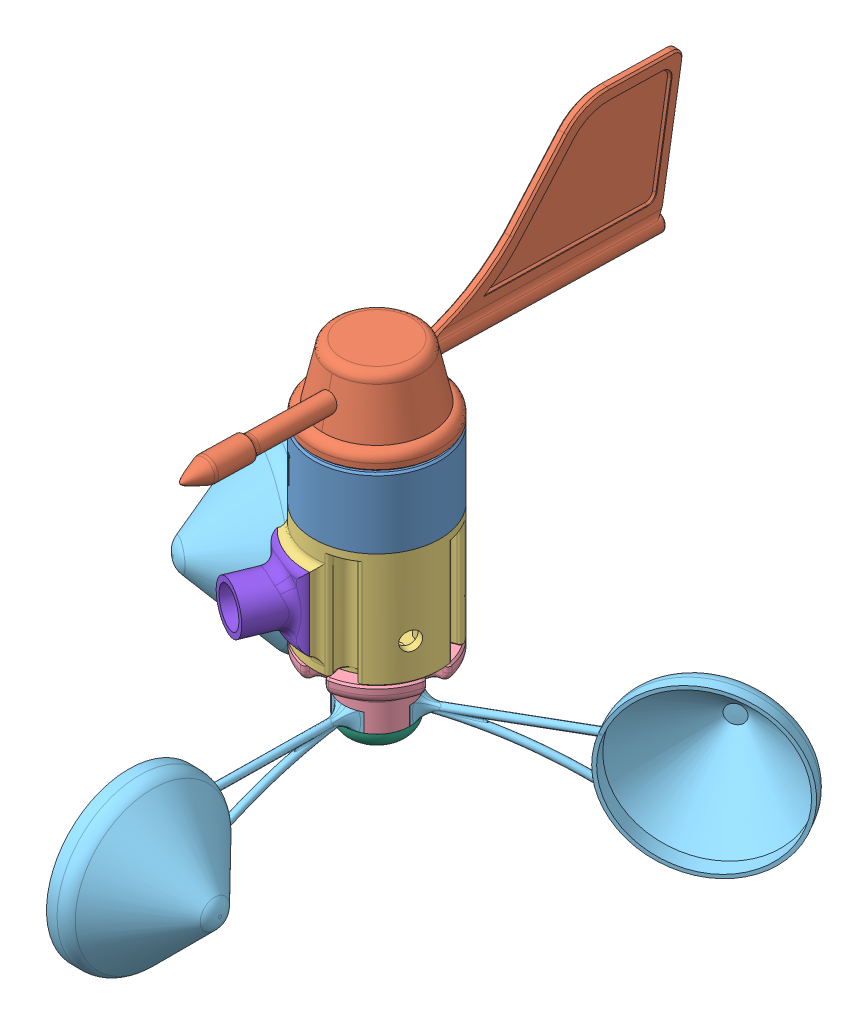
SolidWorks assembly Сборка1, configuration По умолчанию. Lengths in mm.
Overall size (335.22 291.91 357.86).
11 component instances, 8 part files, 27 mates.
Components (placement in the parent):
- втулка1-1: втулка1 [По умолчанию] at (37.1698 47.1282 35.2147) size (69 44 69)
- Деталь2-1: Деталь2 [По умолчанию] at (37.1698 48 35.2147) x (0.999741 0 0.022754) z (-0.022754 0 0.999741) size (69 101.04 267.99)
- втулка2-3: втулка2 [По умолчанию] at (37.1698 -53.8718 35.2147) x (-0.92388 0 0.382683) z (0.382683 0 0.92388) size (71.14 69 71.14)
- Деталь3-2: Деталь3 [По умолчанию] at (37.1698 -53.8718 35.2147) x (-0.999917 0 -0.012913) z (-0.012913 0 0.999917) size (67.85 34 67.85)
- лопасть-1: лопасть [По умолчанию] at (37.1698 -77.8718 35.2147) x (-1 0 0) z (0 0 1) size (163.66 90 113.45)
- лопасть-3: лопасть [По умолчанию] at (37.1698 -77.8718 35.2147) x (0.511141 0 -0.859497) z (-0.859497 0 -0.511141) size (163.66 90 113.45)
- лопасть-4: лопасть [По умолчанию] at (37.1698 -77.8718 35.2147) x (0.488775 0 0.87241) z (0.87241 0 -0.488775) size (163.66 90 113.45)
- крышка-1: крышка [По умолчанию] at (37.1698 -87.8718 35.2147) x (1 0 0) z (0 0 -1) size (36 20 36)
- крышка_бат_отсек-1: крышка_бат_отсек [По умолчанию] at (37.1698 -49.8718 35.2147) x (-0.382683 0 0.92388) z (-0.92388 0 -0.382683) size (27 87.5 4.8)
- крышка_бат_отсек-2: крышка_бат_отсек [По умолчанию] at (37.1698 -49.8718 35.2147) x (-0.92388 0 -0.382683) z (0.382683 0 -0.92388) size (27 87.5 4.8)
- крепление-2: крепление [По умолчанию] at (37.1698 -44.7718 35.2147) x (-0.67559 0 0.737277) z (-0.737277 0 -0.67559) size (36.14 41.34 37.15)
Mates (geometry in assembly coordinates):
- Концентричный1: concentric: circle of втулка1-1; circle of Деталь2-1
- Концентричный2: concentric: circle of втулка1-1; circle of Деталь2-1
- Концентричный3: concentric: circle of Деталь2-1; cylinder of втулка1-1 through (37.1698 9.1282 35.2147) axis (0 1 0) radius 2.5
- Параллельность1: parallel: plane of втулка1-1 through (37.1698 47.1282 35.2147) normal (0 1 0); plane of Деталь2-1 through (37.1698 48 35.2147) normal (0 -1 0)
- Касательность1: tangent: cylinder of втулка1-1 through (37.1698 53.1282 35.2147) axis (0 -1 0) radius 28.5; circle of Деталь2-1
- Совпадение4: coincident: circle of втулка1-1; circle of втулка2-3
- Совпадение5: coincident: circle of втулка2-3; circle of Деталь3-2
- Совпадение7: coincident: circle of Деталь3-2; circle of лопасть-1
- Концентричный5: concentric: circle of Деталь3-2; circle of лопасть-3
- Совпадение11: coincident: line of Деталь3-2 through (32.0584 -67.8718 43.8097) axis (0 -1 0); line of лопасть-3 through (32.0584 -87.8718 43.8097) axis (0 1 0)
- Совпадение13: coincident: circle of Деталь3-2; circle of лопасть-3
- Совпадение18: coincident: circle of Деталь3-2; circle of лопасть-4
- Совпадение19: coincident: line of Деталь3-2 through (19.1713 -77.8718 34.9823) axis (0 -1 0); line of лопасть-4 through (19.1713 -87.8718 34.9823) axis (0 1 0)
- Совпадение20: coincident: circle of Деталь3-2; circle of крышка-1
- Совпадение21: coincident: circle of втулка1-1; circle of втулка2-3
- Совпадение22: coincident: circle of втулка2-3; circle of Деталь3-2
- Совпадение24: coincident: circle of втулка1-1; circle of втулка2-3
- Совпадение25: coincident: cone of втулка2-3 through (37.1698 -52.8718 35.2147) axis (0 -1 0); circle of Деталь3-2
- Совпадение28: coincident: line of втулка1-1 through (3.7612 9.1282 32.7415) axis (0.92388 0 0.382683); line of втулка2-3 through (3.7612 9.1282 32.7415) axis (0.92388 0 0.382683)
- Касательность2: tangent: cylinder of втулка1-1 through (37.1698 26.1282 35.2147) axis (0 -1 0) radius 33.5; cylinder of крышка_бат_отсек-1 through (37.1698 26.1282 35.2147) axis (0 -1 0) radius 33.5
- Совпадение29: coincident: circle of втулка2-3; circle of крышка_бат_отсек-1
- Совпадение30: coincident: point of втулка2-3; point of крышка_бат_отсек-1
- Совпадение31: coincident: point of втулка2-3; point of крышка_бат_отсек-2
- Совпадение32: coincident: circle of втулка2-3; circle of крышка_бат_отсек-2
- Концентричный6: concentric: circle of втулка2-3; circle of крепление-2
- Совпадение40: coincident: line of втулка2-3 through (14.95 -7.8718 64.1721) axis (0 -1 0); line of крепление-2 through (14.95 -7.8718 64.1721) axis (0 -1 0)
- Касательность7: tangent: circle of втулка2-3; plane of крепление-2 through (37.1698 -7.8718 35.2147) normal (0 1 0)
